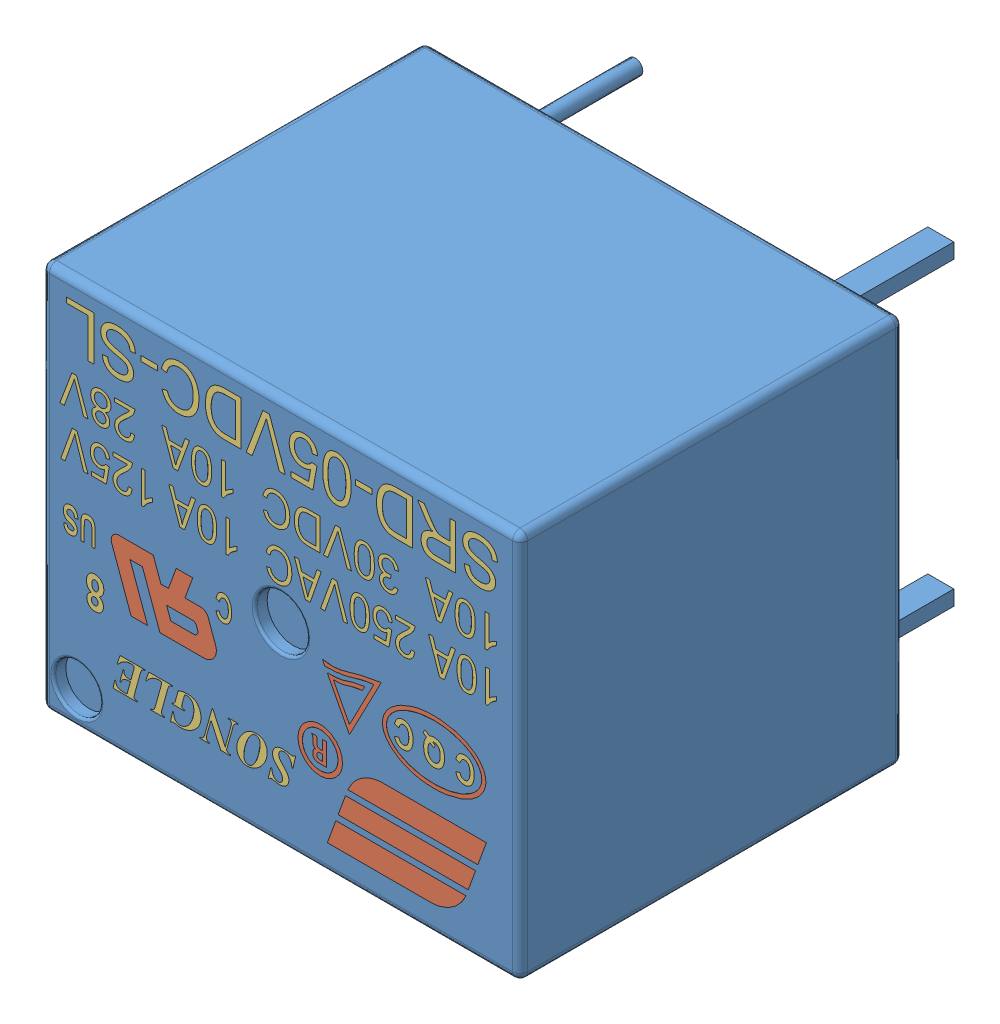
SolidWorks assembly User Library-relay_songle, configuration Default. Lengths in mm.
Overall size (19.1 15.5 20.3).
3 component instances, 3 part files, 0 mates.
Components (placement in the parent):
- User Library-relay_songle_Relay SPDT Songle-1: User Library-relay_songle_Relay SPDT Songle [Default] at (-9.3933 0.0381 20.3) size (19.1 15.5 20.3)
- User Library-relay_songle_logos_1-1: User Library-relay_songle_logos_1 [Default] at (-7.4991 -9.7726 35.1) size (15.17 6.74 0.51)
- User Library-relay_songle_texts_1-1: User Library-relay_songle_texts_1 [Default] at (-9.3933 0.0381 35.1) size (17.52 12.78 0.5)
